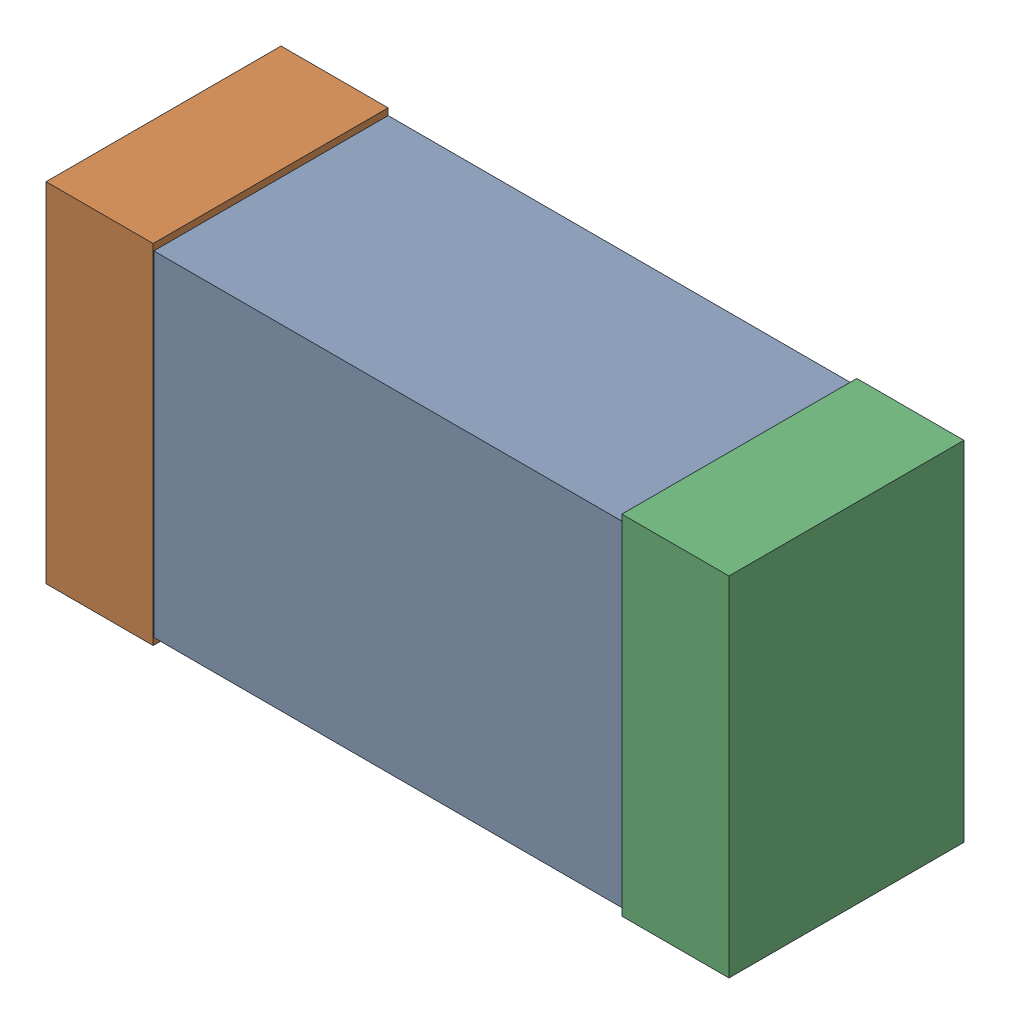
SolidWorks assembly D2, configuration Default. Lengths in mm.
Overall size (1.02 0.52 0.35).
6 component instances, 2 part files, 0 mates.
Components (placement in the parent):
- 870944640-1: 870944640 [Default] at (10.9212 1.0646 0) size (1 0.5 0.35)
  - Extruded_30-1: Extruded_30 [Default] at origin size (1 0.5 0.35)
- 870940480-1: 870940480 [Default] at (10.4912 1.0646 0) size (0.16 0.52 0.35)
  - Extruded-1: Extruded [Default] at origin size (0.16 0.52 0.35)
- 870940480-2: 870940480 [Default] at (11.3512 1.0646 0) size (0.16 0.52 0.35)
  - Extruded-1: Extruded [Default] at origin size (0.16 0.52 0.35)
